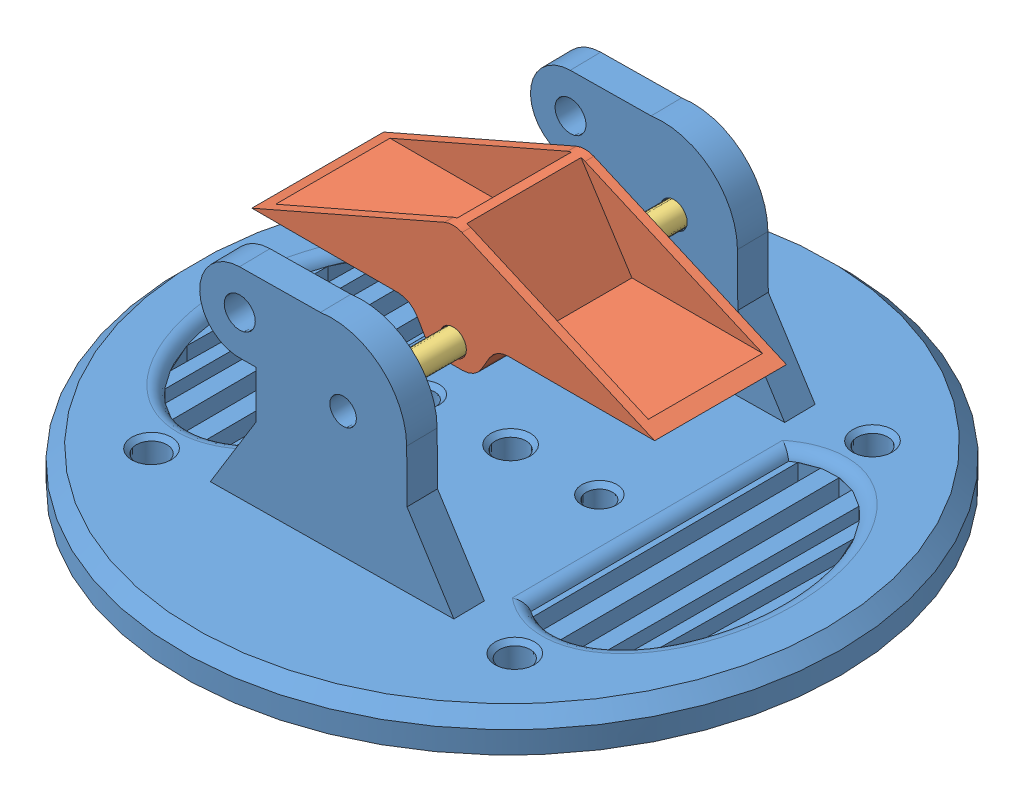
SolidWorks assembly Assemblage1, configuration Défaut. Lengths in mm.
Overall size (212.21 60.58 212.22).
3 component instances, 3 part files, 0 mates.
Components (placement in the parent):
- base-1: base [Défaut] at (9.9345 -30.6159 68.2535) x (0.698823 0.004752 -0.715279) z (0.715292 -0.001761 0.698823) size (150 53.96 150)
- auget-2: auget [Défaut] at (7.1785 9.8969 58.852) size (91.65 27.54 30)
- axe central-1: axe central [Défaut] at (12.3986 6.9514 38.0469) size (5.5 5.5 70)
